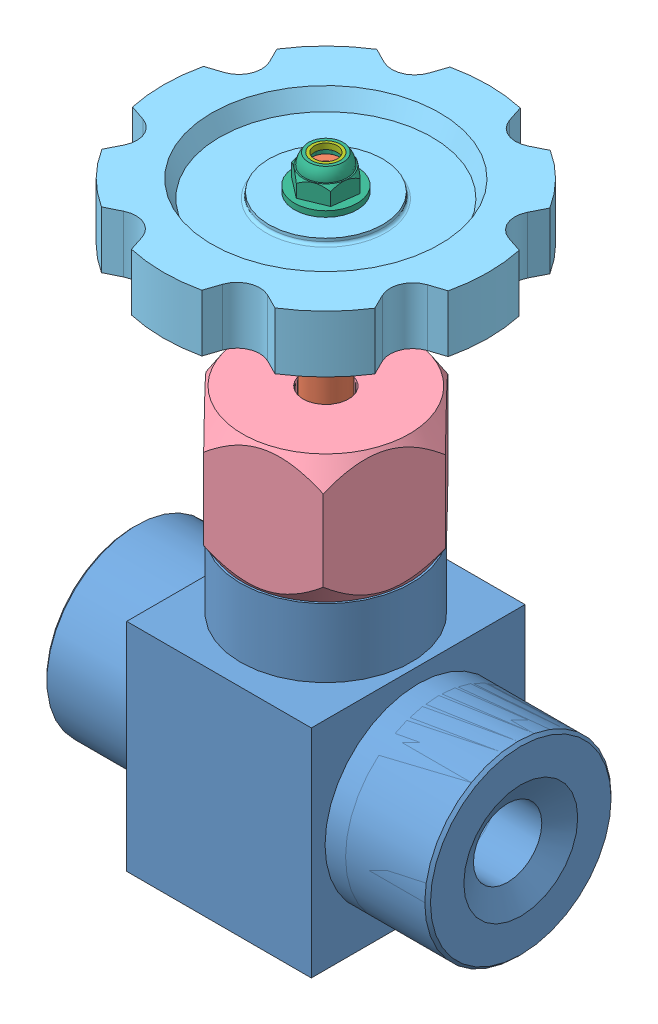
SolidWorks assembly Сборка4, configuration По умолчанию. Lengths in mm.
Overall size (73.23 108 73.23).
7 component instances, 7 part files, 13 mates.
Components (placement in the parent):
- Основание-1: Основание [По умолчанию] at origin size (67.9 70 37.5)
- Тыкалка-1: Тыкалка [По умолчанию] at (16.2 5.0011 18.75) x (0 1 0) z (0.378842 0 0.925461) size (101 9.64 9.17)
- Вещица-2: Вещица [По умолчанию] at (12.2 72 18.75) x (-1 0 0) z (0 1 0) size (19 19 10)
- Накидная_шайба-1: Накидная_шайба [По умолчанию] at (16.2 72.5 18.75) x (0.693565 0 0.720394) z (0.720394 0 -0.693565) size (34.64 22.5 30)
- Шестеренка-1: Шестеренка [По умолчанию] at (16.2 101.0011 18.75) x (0.925461 0 -0.378842) z (-0.378842 0 -0.925461) size (56.15 14 56.15)
- Красное-1: Красное [По умолчанию] at (16.2 102.0011 18.75) x (-0.837169 0 -0.546944) z (0 1 0) size (11 11 6)
- Втулка-1: Втулка [По умолчанию] at (16.2 108.0011 18.75) x (0 -1 0) z (0.08693 0 0.996214) size (1 5 5)
Mates (geometry in assembly coordinates):
- Концентричный2: concentric anti-aligned: cylinder of Основание-1 through (16.2 11 18.75) axis (0 1 0) radius 4.5; cylinder of Тыкалка-1 through (16.2 5.0011 18.75) axis (0 -1 0) radius 3.5
- Совпадение1: coincident aligned: cone of Основание-1 through (16.2 5 18.75) axis (0 -1 0); circle of Тыкалка-1
- Концентричный3: concentric anti-aligned: cylinder of Основание-1 through (16.2 53 18.75) axis (0 1 0) radius 7.85; cylinder of Вещица-2 through (16.2 66.4729 18.75) axis (0 -1 0) radius 8
- Совпадение2: coincident anti-aligned: plane of Основание-1 through (16.2 70 18.75) normal (0 1 0); plane of Вещица-2 through (12.2 70 18.75) normal (0 -1 0)
- Концентричный4: concentric aligned: cylinder of Тыкалка-1 through (16.2 5.0011 18.75) axis (0 -1 0) radius 3.5; cylinder of Накидная_шайба-1 through (16.2 68 18.75) axis (0 -1 0) radius 11
- Совпадение5: coincident anti-aligned: plane of Основание-1 through (16.2 50 18.75) normal (0 1 0); plane of Накидная_шайба-1 through (16.2 50 18.75) normal (0 -1 0)
- Концентричный5: concentric anti-aligned: cylinder of Тыкалка-1 through (16.2 5.0011 18.75) axis (0 -1 0) radius 3.5; cylinder of Шестеренка-1 through (16.2 101.0011 18.75) axis (0 1 0) radius 10
- Совпадение8: coincident anti-aligned: plane of Тыкалка-1 through (19.6594 99.0011 19.2819) normal (0.925461 0 -0.378842); plane of Шестеренка-1 through (20.1129 90.0001 20.3899) normal (-0.925461 0 0.378842)
- Совпадение9: coincident anti-aligned: plane of Тыкалка-1 through (16.2 90.0011 18.75) normal (0 1 0); plane of Шестеренка-1 through (16.2 90.0011 18.75) normal (0 -1 0)
- Концентричный6: concentric aligned: cylinder of Тыкалка-1 through (16.2 106.0011 18.75) axis (0 -1 0) radius 2.5; cylinder of Красное-1 through (16.2 108.0021 18.75) axis (0 -1 0) radius 2.5
- Совпадение10: coincident anti-aligned: plane of Шестеренка-1 through (16.2 102.0011 18.75) normal (0 1 0); plane of Красное-1 through (16.2 102.0011 18.75) normal (0 -1 0)
- Концентричный7: concentric anti-aligned: cylinder of Красное-1 through (16.2 108.0021 18.75) axis (0 -1 0) radius 2.5; cylinder of Втулка-1 through (16.2 107.0011 18.75) axis (0 1 0) radius 2.5
- Совпадение12: coincident aligned: plane of Красное-1 through (16.2 108.0011 18.75) normal (0 1 0); plane of Втулка-1 through (16.2 108.0011 18.75) normal (0 1 0)
